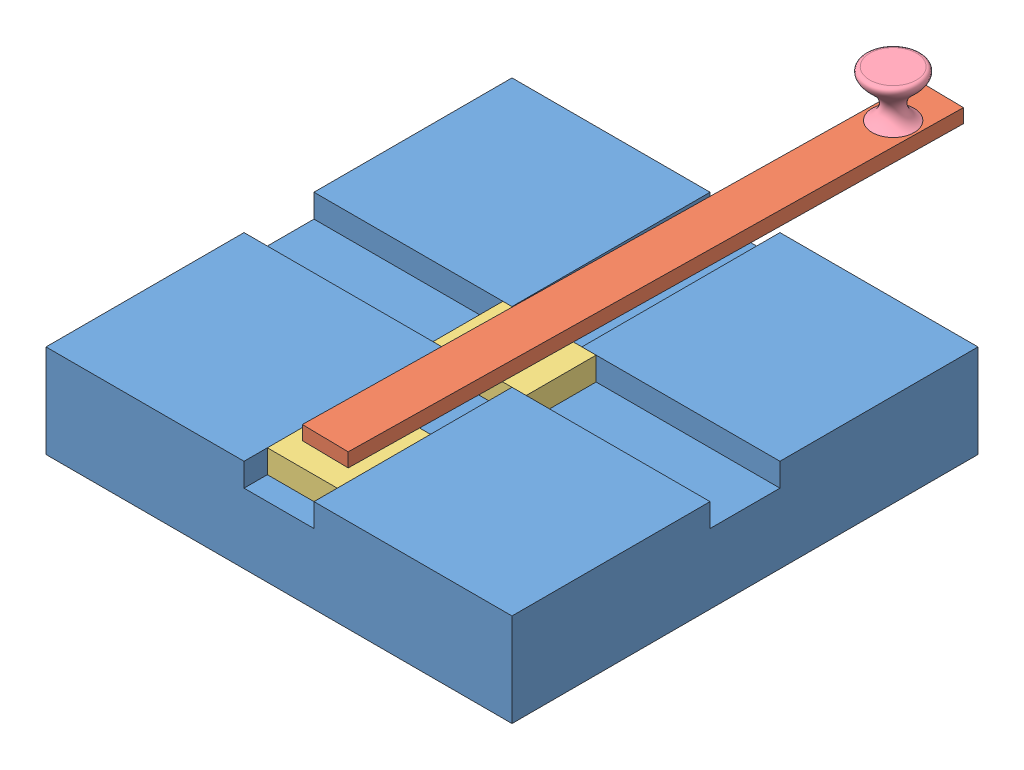
SolidWorks assembly Montagem1, configuration Valor predeterminado. Lengths in mm.
Overall size (100 33 140.07).
5 component instances, 4 part files, 10 mates.
Components (placement in the parent):
- Peça11-1: Peça11 [Valor predeterminado] at (-4.5473 -28.644 100) size (100 20 100)
- Peça10-1: Peça10 [Valor predeterminado] at (-3.605 -5.644 75.0031) x (-0.999877 0 -0.015706) z (0 -1 0) size (10 130 8)
- Peça12-1: Peça12 [Valor predeterminado] at (-3.9976 -8.644 100) x (0 0 -1) z (0 -1 0) size (15 20 5)
- Peça13-1: Peça13 [Valor predeterminado] at (-2.7412 -5.644 20.0099) x (-0.488678 0 0.872464) z (-0.872464 0 -0.488678) size (13.04 13 13.04)
- Peça12-2: Peça12 [Valor predeterminado] at (-4.5473 -8.644 134.9957) x (1 0 0) z (0 -1 0) size (15 20 5)
Mates (geometry in assembly coordinates):
- Concêntrico1: concentric aligned: cylinder of Peça10-1 through (-2.7412 -8.644 20.0099) axis (0 1 0) radius 2.5; cylinder of Peça13-1 through (-2.7412 -8.644 20.0099) axis (0 1 0) radius 2.5
- Coincidente1: coincident anti-aligned: plane of Peça10-1 through (-3.605 -5.644 75.0031) normal (0 1 0); plane of Peça13-1 through (-2.7412 -5.644 20.0099) normal (0 -1 0)
- Coincidente10: coincident anti-aligned: plane of Peça11-1 through (-4.5473 -8.644 100) normal (0 1 0); plane of Peça10-1 through (-3.605 -8.644 75.0031) normal (0 -1 0)
- Coincidente11: coincident anti-aligned: plane of Peça11-1 through (-4.5473 -13.644 100) normal (0 1 0); plane of Peça12-2 through (-4.5473 -13.644 134.9957) normal (0 -1 0)
- Coincidente12: coincident anti-aligned: plane of Peça11-1 through (2.9527 -8.644 100) normal (-1 0 0); plane of Peça12-2 through (2.9527 -13.644 124.9957) normal (1 0 0)
- Coincidente16: coincident anti-aligned: plane of Peça11-1 through (-4.5473 -13.644 100) normal (0 1 0); plane of Peça12-1 through (-3.9976 -13.644 100) normal (0 -1 0)
- Coincidente17: coincident anti-aligned: plane of Peça11-1 through (-4.5473 -8.644 92.5) normal (0 0 1); plane of Peça12-1 through (-13.9976 -13.644 92.5) normal (0 0 -1)
- Concêntrico2: concentric aligned: cylinder of Peça10-1 through (-4.5473 -13.644 134.9957) axis (0 1 0) radius 2.5; cylinder of Peça12-2 through (-4.5473 -13.644 134.9957) axis (0 1 0) radius 2.5
- Concêntrico3: concentric aligned: cylinder of Peça10-1 through (-3.9976 -13.644 100) axis (0 1 0) radius 2.5; cylinder of Peça12-1 through (-3.9976 -13.644 100) axis (0 1 0) radius 2.5
- DistânciaLimite1: limit distance = 39.4503 mm aligned: plane of Peça11-1 through (45.4527 -13.644 100) normal (1 0 0); plane of Peça12-1 through (6.0024 -13.644 92.5) normal (1 0 0)
